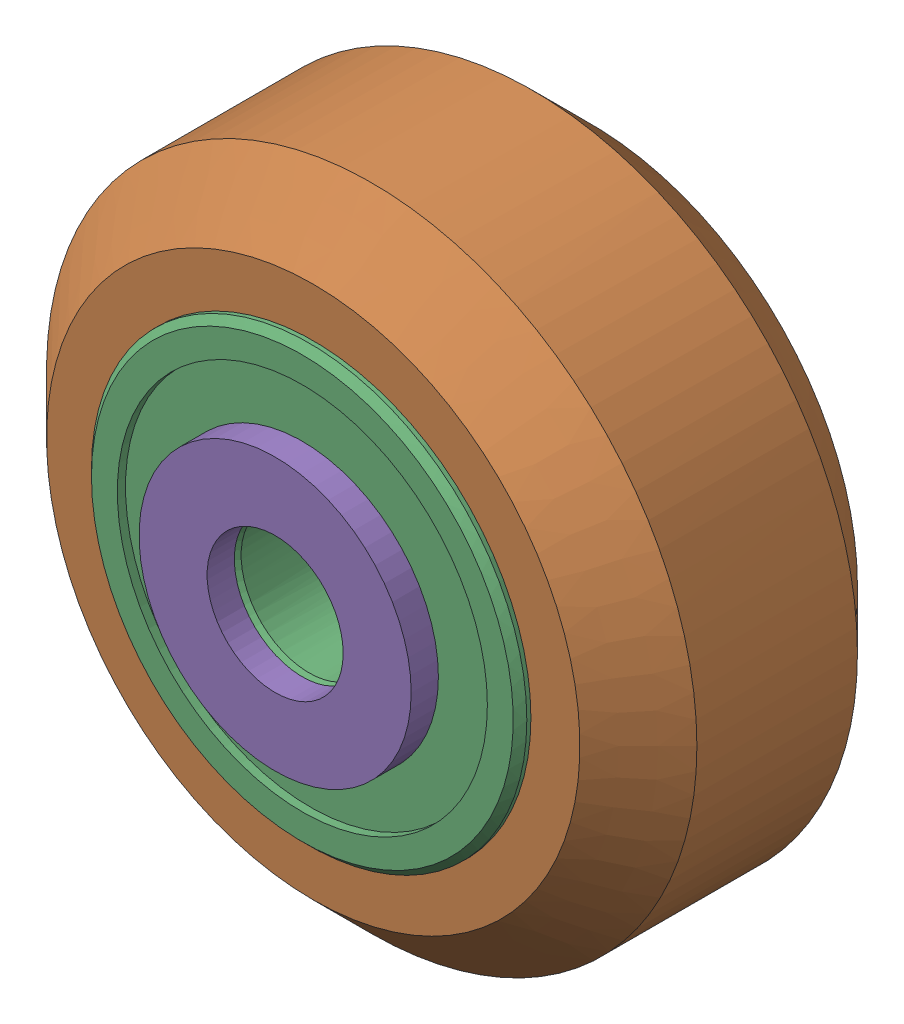
SolidWorks assembly Xtreme Solid V Wheel Kit Assembly_6, configuration Default. Lengths in mm.
Overall size (23.9 23.9 13).
6 component instances, 3 part files, 0 mates.
Components (placement in the parent):
- Precision Shim - 10x5x1mm-1: Precision Shim - 10x5x1mm [Default] at origin size (10 10 1)
- Xtreme Solid V Wheel Assembly_6-1: Xtreme Solid V Wheel Assembly_6 [Default] at (115.15 55.79 -23.5) size (23.9 23.9 11)
  - Xtreme Solid V Wheel-1: Xtreme Solid V Wheel [Default] at (-115.15 -55.79 30) x (0 0 1) z (-1 0 0) size (10.2 23.9 23.9)
  - Wheel+Kit+-+5x16x5mm+Sealed+Radial+Ball+Bearing.step.f3d-1: Wheel+Kit+-+5x16x5mm+Sealed+Radial+Ball+Bearing.step.f3d [Default] at (-115.15 -55.79 30) x (0 1 0) z (-1 0 0) size (16 5 16)
  - Wheel+Kit+-+5x16x5mm+Sealed+Radial+Ball+Bearing.step.f3d-2: Wheel+Kit+-+5x16x5mm+Sealed+Radial+Ball+Bearing.step.f3d [Default] at (-115.15 -55.79 30) x (0 1 0) z (1 0 0) size (16 5 16)
- Precision Shim - 10x5x1mm-2: Precision Shim - 10x5x1mm [Default] at (0 0 12) size (10 10 1)
